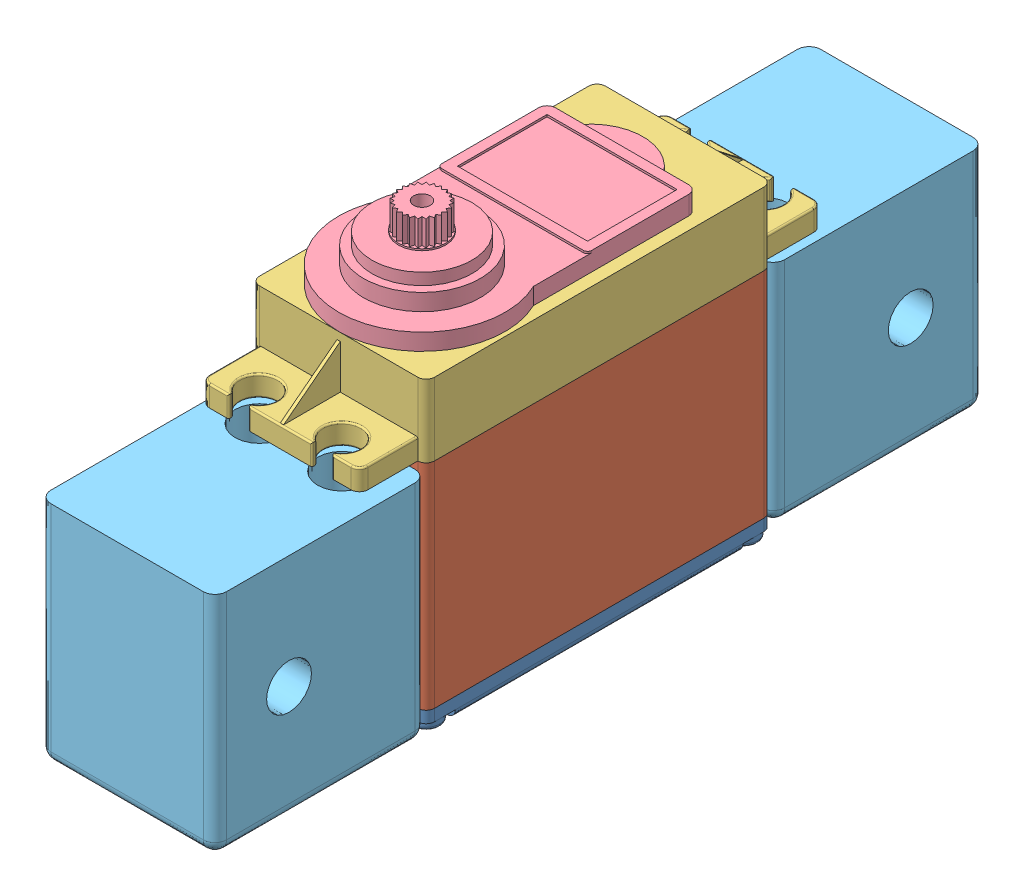
SolidWorks assembly MS-A-0013a-Hand Servo Mount Assembly, configuration Default. Lengths in mm.
Overall size (21.09 45.49 92.36).
7 component instances, 5 part files, 7 mates.
Components (placement in the parent):
- 11886-2: 11886 [Default] at (-16.5206 37.1922 18.007) size (21 45.43 55.5)
  - 11886_bottom-1: 11886_bottom [Default] at (2.2223 -4.2785 0.9275) size (21 2.43 41.5)
  - 11886_middle-1: 11886_middle [Default] at (2.2223 -1.8785 0.9275) size (21 25.7 42.9)
  - 11886_upper-1: 11886_upper [Default] at (6.1473 23.8215 -5.3225) size (21 8.72 55.5)
  - 11886_top-1: 11886_top [Default] at (2.2223 32.5215 0.7275) size (20 8.6 36.5)
- MS-P-0055-Hand Servo Mount-1: MS-P-0055-Hand Servo Mount [Default] at (-14.2513 32.8197 52.4125) x (0 0 1) z (-1 0 0) size (25.4 27.18 21.08)
- MS-P-0055-Hand Servo Mount-2: MS-P-0055-Hand Servo Mount [Default] at (-14.2513 33.8357 -14.5435) x (0 0 -1) z (1 0 0) size (25.4 27.18 21.08)
Mates (geometry in assembly coordinates):
- Concentric1: concentric anti-aligned: circle of 11886-2/11886_upper-1; circle of ClawServoSideMountLDPRT-1
- Parallel1: parallel aligned: plane of 11886-2/11886_bottom-1 through (-24.7983 32.9137 -1.8155) normal (0 -1 0); plane of ClawServoSideMount-1 through (-14.2513 32.8197 52.4125) normal (0 -1 0)
- Parallel2: parallel aligned: plane of 11886-2/11886_middle-1 through (-3.7983 61.0137 39.6845) normal (1 0 0); plane of ClawServoSideMount-1 through (-3.7103 59.9977 39.7125) normal (1 0 0)
- Concentric8: concentric anti-aligned: circle of 11886-2/11886_upper-1; circle of ClawServoSideMountLDPRT-2
- Parallel3: parallel aligned: plane of 11886-2/11886_middle-1 through (-3.7983 61.0137 39.6845) normal (1 0 0); plane of ClawServoSideMount-2 through (-3.7103 61.0137 -1.8435) normal (1 0 0)
- Parallel4: parallel aligned: plane of 11886-2/11886_bottom-1 through (-24.7983 32.9137 -1.8155) normal (0 -1 0); plane of ClawServoSideMount-2 through (-14.2513 33.8357 -14.5435) normal (0 -1 0)
- Distance2: distance = 1.016 mm anti-aligned: plane of ClawServoSideMount-1 through (-14.2513 59.9977 52.4125) normal (0 1 0); plane of 11886-2/11886_upper-1 through (-24.7983 61.0137 -1.8155) normal (0 -1 0)
